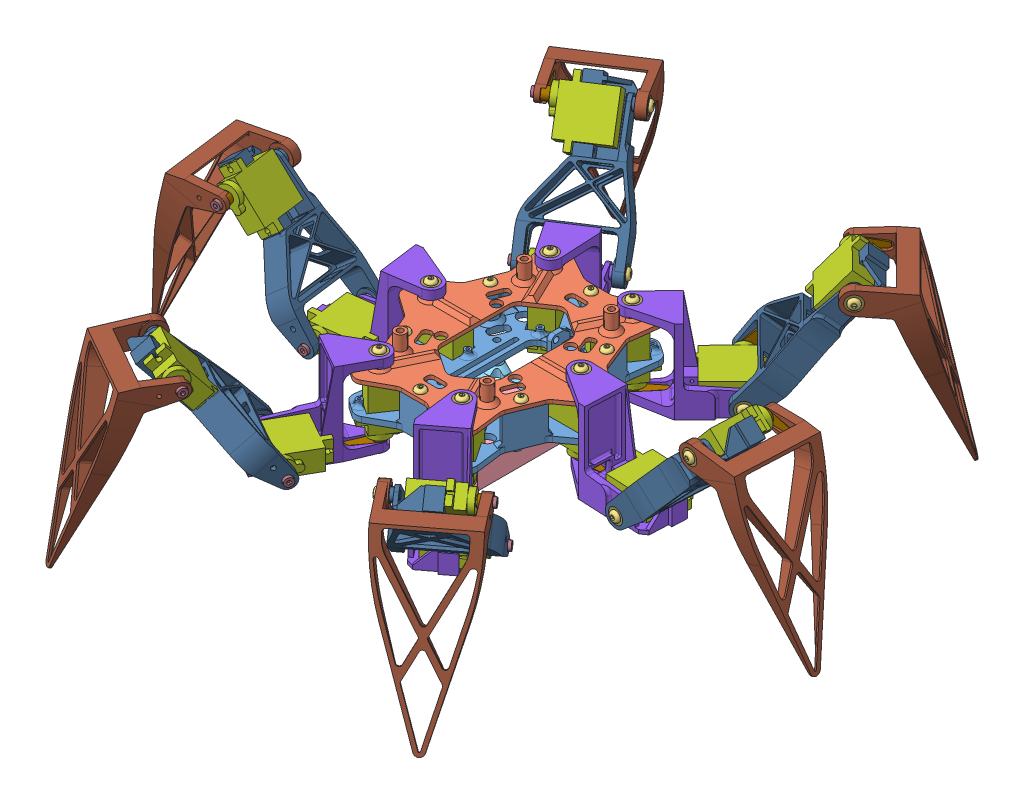
SolidWorks assembly Spider, configuration Default. Lengths in mm.
Overall size (363.71 100.91 356.3).
142 component instances, 13 part files, 63 mates.
Components (placement in the parent):
- Base-1: Base [Default] at (36.3736 62.9905 92.2732) size (103.38 18 115.92)
- Top-1: Top [Default] at (36.3236 80.9905 92.3982) size (103.88 12 115.92)
- m3x8 button-1: m3x8 button [Default] at (67.7613 84.6405 115.5337) x (0 -1 0) z (-0.034129 0 0.999417) size (9.65 5.7 5.7)
- m3x8 button-2: m3x8 button [Default] at (36.3236 84.6405 138.3982) x (0 -1 0) z (0.154828 0 0.987941) size (9.65 5.7 5.7)
- m3x8 button-3: m3x8 button [Default] at (4.8859 84.6405 115.5337) x (0 -1 0) z (0.364161 0 0.931336) size (9.65 5.7 5.7)
- m3x8 button-4: m3x8 button [Default] at (4.8859 84.6405 69.2627) x (0 -1 0) z (0.572348 0 0.820011) size (9.65 5.7 5.7)
- m3x8 button-5: m3x8 button [Default] at (36.3236 84.6405 46.3982) x (0 -1 0) z (0.751604 0 0.659615) size (9.65 5.7 5.7)
- m3x8 button-6: m3x8 button [Default] at (67.7613 84.6405 69.2627) x (0 -1 0) z (0.880548 0 0.473957) size (9.65 5.7 5.7)
- Battery-1: Battery [Default] at (36.3736 35.9905 92.2732) x (0 0 -1) z (1 0 0) size (62 15 31)
- battery_mount-1: battery_mount [Default] at (36.3736 50.9905 92.2732) x (0 0 1) z (-1 0 0) size (36.78 12 46.78)
- threaded insert-4: threaded insert [Default] at (58.6155 81.7905 138.3982) size (4 4.7 4)
- threaded insert-5: threaded insert [Default] at (14.0317 81.7905 138.3982) x (0.982082 0 -0.188455) z (0.188455 0 0.982082) size (4 4.7 4)
- threaded insert-6: threaded insert [Default] at (-4.3683 81.7905 92.3982) x (0.918365 0 -0.395734) z (0.395734 0 0.918365) size (4 4.7 4)
- threaded insert-7: threaded insert [Default] at (14.0317 81.7905 46.3982) x (0.8 0 -0.6) z (0.6 0 0.8) size (4 4.7 4)
- threaded insert-8: threaded insert [Default] at (58.6155 81.7905 46.3982) x (0.63358 0 -0.773678) z (0.773678 0 0.63358) size (4 4.7 4)
- threaded insert-9: threaded insert [Default] at (77.0155 81.7905 92.3982) x (0.443629 0 -0.896211) z (0.896211 0 0.443629) size (4 4.7 4)
- MG90S Servo-1: MG90S Servo [Default] at (55.3718 78.9905 133.4083) x (0.560629 0 0.828067) z (0.828067 0 -0.560629) size (32 30 11)
- MG90S Servo-2: MG90S Servo [Default] at (70.9405 78.9905 92.2732) x (1 0 0) z (0 0 -1) size (32 30 11)
- MG90S Servo-3: MG90S Servo [Default] at (55.3718 78.9905 51.1381) x (0.560629 0 -0.828067) z (-0.828067 0 -0.560629) size (32 30 11)
- MG90S Servo-4: MG90S Servo [Default] at (17.3754 78.9905 51.1381) x (-0.560629 0 -0.828067) z (-0.828067 0 0.560629) size (32 30 11)
- MG90S Servo-5: MG90S Servo [Default] at (1.8067 78.9905 92.2732) x (-1 0 0) z (0 0 1) size (32 30 11)
- MG90S Servo-6: MG90S Servo [Default] at (17.3754 78.9905 133.4083) x (-0.560629 0 0.828067) z (0.828067 0 0.560629) size (32 30 11)
- leg-9: leg [Default] at (95.2085 35.4236 45.2462) x (0.998917 0 0.046534) z (-0.046534 0 0.998917) size (145.56 100.91 49.06)
  - hip-1: hip [Default] at (3.5209 10.0668 41.9475) size (59.25 45 23)
  - MG90S Servo-1: MG90S Servo [Default] at (20.5209 18.3168 57.9475) x (1 0 0) z (0 1 0) size (32 30 11)
  - servo horn-1: servo horn [Default] at (26.5209 18.3168 26.9475) x (0.646712 0.762734 0) z (0.762734 -0.646712 0) size (17.5 3.5 6)
  - threaded insert-1: threaded insert [Default] at (26.5209 18.3168 64.9475) x (-0.923728 -0.383049 0) z (0.383049 -0.923728 0) size (4 4.7 4)
  - thigh-1: thigh [Default] at (59.9753 45.0163 41.9475) x (0.646712 0.762734 0) z (0 0 1) size (81.75 14.22 44.5)
  - MG90S Servo-2: MG90S Servo [Default] at (64.6769 63.3181 57.9475) x (0.646712 0.762734 0) z (-0.762734 0.646712 0) size (32 30 11)
  - threaded insert-2: threaded insert [Default] at (68.5572 67.8945 60.2475) x (-0.923728 -0.383049 0) z (-0.383049 0.923728 0) size (4 4.7 4)
  - servo horn-2: servo horn [Default] at (68.5572 67.8945 26.9475) x (0.996071 -0.088554 0) z (-0.088554 -0.996071 0) size (17.5 3.5 6)
  - shin curved-1: shin curved [Default] at (168.1643 59.0391 46.6975) x (0 0 -1) z (0.088554 0.996071 0) size (49.06 60.96 90.13)
  - 693zz-1: 693zz [Default] at (26.5209 18.3168 64.9475) x (0.87068 -0.491851 0) z (-0.491851 -0.87068 0) size (8 4 8)
  - 693zz-2: 693zz [Default] at (68.5572 67.8945 64.9475) x (0.93765 -0.34758 0) z (-0.34758 -0.93765 0) size (8 4 8)
  - m3x8 button-1: m3x8 button [Default] at (26.5209 18.3168 70.5975) x (0 0 -1) z (1 0 0) size (9.65 5.7 5.7)
  - m3x8 button-5: m3x8 button [Default] at (68.5572 67.8945 70.5975) x (0 0 -1) z (1 0 0) size (9.65 5.7 5.7)
  - M2.5X8 Cap Head-1: M2.5X8 Cap Head [Default] at (26.5209 18.3168 22.9475) x (0 0 1) z (-0.556527 0.83083 0) size (8.5 4.5 4.5)
  - M2.5X8 Cap Head-2: M2.5X8 Cap Head [Default] at (68.5572 67.8945 22.9475) x (0 0 1) z (0.690395 0.723432 0) size (8.5 4.5 4.5)
  - servo horn-3: servo horn [Default] at (-15.9791 12.5668 47.9475) size (17.5 3.5 6)
  - 693zz-4: 693zz [Default] at (-15.9791 51.0668 47.9475) x (0.999788 0 -0.020572) z (0.020572 0 0.999788) size (8 4 8)
  - m3x8 button-7: m3x8 button [Default] at (-15.9791 56.7168 47.9475) x (0 -1 0) z (1 0 0) size (9.65 5.7 5.7)
  - M2.5X8 Cap Head-3: M2.5X8 Cap Head [Default] at (-15.9791 8.5668 47.9475) x (0 1 0) z (0 0 1) size (8.5 4.5 4.5)
- leg-11: leg [Default] at (35.8596 35.4236 1.271) x (0.704741 0 -0.709465) z (0.709465 0 0.704741) size (145.56 100.91 49.06)
  - hip-1: hip [Default] at (3.5209 10.0668 41.9475) size (59.25 45 23)
  - MG90S Servo-1: MG90S Servo [Default] at (20.5209 18.3168 57.9475) x (1 0 0) z (0 1 0) size (32 30 11)
  - servo horn-1: servo horn [Default] at (26.5209 18.3168 26.9475) x (0.646712 0.762734 0) z (0.762734 -0.646712 0) size (17.5 3.5 6)
  - threaded insert-1: threaded insert [Default] at (26.5209 18.3168 64.9475) x (-0.923728 -0.383049 0) z (0.383049 -0.923728 0) size (4 4.7 4)
  - thigh-1: thigh [Default] at (59.9753 45.0163 41.9475) x (0.646712 0.762734 0) z (0 0 1) size (81.75 14.22 44.5)
  - MG90S Servo-2: MG90S Servo [Default] at (64.6769 63.3181 57.9475) x (0.646712 0.762734 0) z (-0.762734 0.646712 0) size (32 30 11)
  - threaded insert-2: threaded insert [Default] at (68.5572 67.8945 60.2475) x (-0.923728 -0.383049 0) z (-0.383049 0.923728 0) size (4 4.7 4)
  - servo horn-2: servo horn [Default] at (68.5572 67.8945 26.9475) x (0.996071 -0.088554 0) z (-0.088554 -0.996071 0) size (17.5 3.5 6)
  - shin curved-1: shin curved [Default] at (168.1643 59.0391 46.6975) x (0 0 -1) z (0.088554 0.996071 0) size (49.06 60.96 90.13)
  - 693zz-1: 693zz [Default] at (26.5209 18.3168 64.9475) x (0.87068 -0.491851 0) z (-0.491851 -0.87068 0) size (8 4 8)
  - 693zz-2: 693zz [Default] at (68.5572 67.8945 64.9475) x (0.93765 -0.34758 0) z (-0.34758 -0.93765 0) size (8 4 8)
  - m3x8 button-1: m3x8 button [Default] at (26.5209 18.3168 70.5975) x (0 0 -1) z (1 0 0) size (9.65 5.7 5.7)
  - m3x8 button-5: m3x8 button [Default] at (68.5572 67.8945 70.5975) x (0 0 -1) z (1 0 0) size (9.65 5.7 5.7)
  - M2.5X8 Cap Head-1: M2.5X8 Cap Head [Default] at (26.5209 18.3168 22.9475) x (0 0 1) z (-0.556527 0.83083 0) size (8.5 4.5 4.5)
  - M2.5X8 Cap Head-2: M2.5X8 Cap Head [Default] at (68.5572 67.8945 22.9475) x (0 0 1) z (0.690395 0.723432 0) size (8.5 4.5 4.5)
  - servo horn-3: servo horn [Default] at (-15.9791 12.5668 47.9475) size (17.5 3.5 6)
  - 693zz-4: 693zz [Default] at (-15.9791 51.0668 47.9475) x (0.999788 0 -0.020572) z (0.020572 0 0.999788) size (8 4 8)
  - m3x8 button-7: m3x8 button [Default] at (-15.9791 56.7168 47.9475) x (0 -1 0) z (1 0 0) size (9.65 5.7 5.7)
  - M2.5X8 Cap Head-3: M2.5X8 Cap Head [Default] at (-15.9791 8.5668 47.9475) x (0 1 0) z (0 0 1) size (8.5 4.5 4.5)
- leg-13: leg [Default] at (-34.8765 35.4236 58.9854) x (-0.546402 0 -0.837523) z (0.837523 0 -0.546402) size (145.56 100.91 49.06)
  - hip-1: hip [Default] at (3.5209 10.0668 41.9475) size (59.25 45 23)
  - MG90S Servo-1: MG90S Servo [Default] at (20.5209 18.3168 57.9475) x (1 0 0) z (0 1 0) size (32 30 11)
  - servo horn-1: servo horn [Default] at (26.5209 18.3168 26.9475) x (0.646712 0.762734 0) z (0.762734 -0.646712 0) size (17.5 3.5 6)
  - threaded insert-1: threaded insert [Default] at (26.5209 18.3168 64.9475) x (-0.923728 -0.383049 0) z (0.383049 -0.923728 0) size (4 4.7 4)
  - thigh-1: thigh [Default] at (59.9753 45.0163 41.9475) x (0.646712 0.762734 0) z (0 0 1) size (81.75 14.22 44.5)
  - MG90S Servo-2: MG90S Servo [Default] at (64.6769 63.3181 57.9475) x (0.646712 0.762734 0) z (-0.762734 0.646712 0) size (32 30 11)
  - threaded insert-2: threaded insert [Default] at (68.5572 67.8945 60.2475) x (-0.923728 -0.383049 0) z (-0.383049 0.923728 0) size (4 4.7 4)
  - servo horn-2: servo horn [Default] at (68.5572 67.8945 26.9475) x (0.996071 -0.088554 0) z (-0.088554 -0.996071 0) size (17.5 3.5 6)
  - shin curved-1: shin curved [Default] at (168.1643 59.0391 46.6975) x (0 0 -1) z (0.088554 0.996071 0) size (49.06 60.96 90.13)
  - 693zz-1: 693zz [Default] at (26.5209 18.3168 64.9475) x (0.87068 -0.491851 0) z (-0.491851 -0.87068 0) size (8 4 8)
  - 693zz-2: 693zz [Default] at (68.5572 67.8945 64.9475) x (0.93765 -0.34758 0) z (-0.34758 -0.93765 0) size (8 4 8)
  - m3x8 button-1: m3x8 button [Default] at (26.5209 18.3168 70.5975) x (0 0 -1) z (1 0 0) size (9.65 5.7 5.7)
  - m3x8 button-5: m3x8 button [Default] at (68.5572 67.8945 70.5975) x (0 0 -1) z (1 0 0) size (9.65 5.7 5.7)
  - M2.5X8 Cap Head-1: M2.5X8 Cap Head [Default] at (26.5209 18.3168 22.9475) x (0 0 1) z (-0.556527 0.83083 0) size (8.5 4.5 4.5)
  - M2.5X8 Cap Head-2: M2.5X8 Cap Head [Default] at (68.5572 67.8945 22.9475) x (0 0 1) z (0.690395 0.723432 0) size (8.5 4.5 4.5)
  - servo horn-3: servo horn [Default] at (-15.9791 12.5668 47.9475) size (17.5 3.5 6)
  - 693zz-4: 693zz [Default] at (-15.9791 51.0668 47.9475) x (0.999788 0 -0.020572) z (0.020572 0 0.999788) size (8 4 8)
  - m3x8 button-7: m3x8 button [Default] at (-15.9791 56.7168 47.9475) x (0 -1 0) z (1 0 0) size (9.65 5.7 5.7)
  - M2.5X8 Cap Head-3: M2.5X8 Cap Head [Default] at (-15.9791 8.5668 47.9475) x (0 1 0) z (0 0 1) size (8.5 4.5 4.5)
- leg-15: leg [Default] at (-13.8109 35.4236 141.8897) x (-0.991533 0 0.129855) z (-0.129855 0 -0.991533) size (145.56 100.91 49.06)
  - hip-1: hip [Default] at (3.5209 10.0668 41.9475) size (59.25 45 23)
  - MG90S Servo-1: MG90S Servo [Default] at (20.5209 18.3168 57.9475) x (1 0 0) z (0 1 0) size (32 30 11)
  - servo horn-1: servo horn [Default] at (26.5209 18.3168 26.9475) x (0.646712 0.762734 0) z (0.762734 -0.646712 0) size (17.5 3.5 6)
  - threaded insert-1: threaded insert [Default] at (26.5209 18.3168 64.9475) x (-0.923728 -0.383049 0) z (0.383049 -0.923728 0) size (4 4.7 4)
  - thigh-1: thigh [Default] at (59.9753 45.0163 41.9475) x (0.646712 0.762734 0) z (0 0 1) size (81.75 14.22 44.5)
  - MG90S Servo-2: MG90S Servo [Default] at (64.6769 63.3181 57.9475) x (0.646712 0.762734 0) z (-0.762734 0.646712 0) size (32 30 11)
  - threaded insert-2: threaded insert [Default] at (68.5572 67.8945 60.2475) x (-0.923728 -0.383049 0) z (-0.383049 0.923728 0) size (4 4.7 4)
  - servo horn-2: servo horn [Default] at (68.5572 67.8945 26.9475) x (0.996071 -0.088554 0) z (-0.088554 -0.996071 0) size (17.5 3.5 6)
  - shin curved-1: shin curved [Default] at (168.1643 59.0391 46.6975) x (0 0 -1) z (0.088554 0.996071 0) size (49.06 60.96 90.13)
  - 693zz-1: 693zz [Default] at (26.5209 18.3168 64.9475) x (0.87068 -0.491851 0) z (-0.491851 -0.87068 0) size (8 4 8)
  - 693zz-2: 693zz [Default] at (68.5572 67.8945 64.9475) x (0.93765 -0.34758 0) z (-0.34758 -0.93765 0) size (8 4 8)
  - m3x8 button-1: m3x8 button [Default] at (26.5209 18.3168 70.5975) x (0 0 -1) z (1 0 0) size (9.65 5.7 5.7)
  - m3x8 button-5: m3x8 button [Default] at (68.5572 67.8945 70.5975) x (0 0 -1) z (1 0 0) size (9.65 5.7 5.7)
  - M2.5X8 Cap Head-1: M2.5X8 Cap Head [Default] at (26.5209 18.3168 22.9475) x (0 0 1) z (-0.556527 0.83083 0) size (8.5 4.5 4.5)
  - M2.5X8 Cap Head-2: M2.5X8 Cap Head [Default] at (68.5572 67.8945 22.9475) x (0 0 1) z (0.690395 0.723432 0) size (8.5 4.5 4.5)
  - servo horn-3: servo horn [Default] at (-15.9791 12.5668 47.9475) size (17.5 3.5 6)
  - 693zz-4: 693zz [Default] at (-15.9791 51.0668 47.9475) x (0.999788 0 -0.020572) z (0.020572 0 0.999788) size (8 4 8)
  - m3x8 button-7: m3x8 button [Default] at (-15.9791 56.7168 47.9475) x (0 -1 0) z (1 0 0) size (9.65 5.7 5.7)
  - M2.5X8 Cap Head-3: M2.5X8 Cap Head [Default] at (-15.9791 8.5668 47.9475) x (0 1 0) z (0 0 1) size (8.5 4.5 4.5)
- leg-17: leg [Default] at (47.7955 35.4236 175.9659) x (-0.494254 0 0.869317) z (-0.869317 0 -0.494254) size (145.56 100.91 49.06)
  - hip-1: hip [Default] at (3.5209 10.0668 41.9475) size (59.25 45 23)
  - MG90S Servo-1: MG90S Servo [Default] at (20.5209 18.3168 57.9475) x (1 0 0) z (0 1 0) size (32 30 11)
  - servo horn-1: servo horn [Default] at (26.5209 18.3168 26.9475) x (0.646712 0.762734 0) z (0.762734 -0.646712 0) size (17.5 3.5 6)
  - threaded insert-1: threaded insert [Default] at (26.5209 18.3168 64.9475) x (-0.923728 -0.383049 0) z (0.383049 -0.923728 0) size (4 4.7 4)
  - thigh-1: thigh [Default] at (59.9753 45.0163 41.9475) x (0.646712 0.762734 0) z (0 0 1) size (81.75 14.22 44.5)
  - MG90S Servo-2: MG90S Servo [Default] at (64.6769 63.3181 57.9475) x (0.646712 0.762734 0) z (-0.762734 0.646712 0) size (32 30 11)
  - threaded insert-2: threaded insert [Default] at (68.5572 67.8945 60.2475) x (-0.923728 -0.383049 0) z (-0.383049 0.923728 0) size (4 4.7 4)
  - servo horn-2: servo horn [Default] at (68.5572 67.8945 26.9475) x (0.996071 -0.088554 0) z (-0.088554 -0.996071 0) size (17.5 3.5 6)
  - shin curved-1: shin curved [Default] at (168.1643 59.0391 46.6975) x (0 0 -1) z (0.088554 0.996071 0) size (49.06 60.96 90.13)
  - 693zz-1: 693zz [Default] at (26.5209 18.3168 64.9475) x (0.87068 -0.491851 0) z (-0.491851 -0.87068 0) size (8 4 8)
  - 693zz-2: 693zz [Default] at (68.5572 67.8945 64.9475) x (0.93765 -0.34758 0) z (-0.34758 -0.93765 0) size (8 4 8)
  - m3x8 button-1: m3x8 button [Default] at (26.5209 18.3168 70.5975) x (0 0 -1) z (1 0 0) size (9.65 5.7 5.7)
  - m3x8 button-5: m3x8 button [Default] at (68.5572 67.8945 70.5975) x (0 0 -1) z (1 0 0) size (9.65 5.7 5.7)
  - M2.5X8 Cap Head-1: M2.5X8 Cap Head [Default] at (26.5209 18.3168 22.9475) x (0 0 1) z (-0.556527 0.83083 0) size (8.5 4.5 4.5)
  - M2.5X8 Cap Head-2: M2.5X8 Cap Head [Default] at (68.5572 67.8945 22.9475) x (0 0 1) z (0.690395 0.723432 0) size (8.5 4.5 4.5)
  - servo horn-3: servo horn [Default] at (-15.9791 12.5668 47.9475) size (17.5 3.5 6)
  - 693zz-4: 693zz [Default] at (-15.9791 51.0668 47.9475) x (0.999788 0 -0.020572) z (0.020572 0 0.999788) size (8 4 8)
  - m3x8 button-7: m3x8 button [Default] at (-15.9791 56.7168 47.9475) x (0 -1 0) z (1 0 0) size (9.65 5.7 5.7)
  - M2.5X8 Cap Head-3: M2.5X8 Cap Head [Default] at (-15.9791 8.5668 47.9475) x (0 1 0) z (0 0 1) size (8.5 4.5 4.5)
- leg-19: leg [Default] at (106.5656 35.4236 122.0493) x (0.605702 0 0.795692) z (-0.795692 0 0.605702) size (145.56 100.91 49.06)
  - hip-1: hip [Default] at (3.5209 10.0668 41.9475) size (59.25 45 23)
  - MG90S Servo-1: MG90S Servo [Default] at (20.5209 18.3168 57.9475) x (1 0 0) z (0 1 0) size (32 30 11)
  - servo horn-1: servo horn [Default] at (26.5209 18.3168 26.9475) x (0.646712 0.762734 0) z (0.762734 -0.646712 0) size (17.5 3.5 6)
  - threaded insert-1: threaded insert [Default] at (26.5209 18.3168 64.9475) x (-0.923728 -0.383049 0) z (0.383049 -0.923728 0) size (4 4.7 4)
  - thigh-1: thigh [Default] at (59.9753 45.0163 41.9475) x (0.646712 0.762734 0) z (0 0 1) size (81.75 14.22 44.5)
  - MG90S Servo-2: MG90S Servo [Default] at (64.6769 63.3181 57.9475) x (0.646712 0.762734 0) z (-0.762734 0.646712 0) size (32 30 11)
  - threaded insert-2: threaded insert [Default] at (68.5572 67.8945 60.2475) x (-0.923728 -0.383049 0) z (-0.383049 0.923728 0) size (4 4.7 4)
  - servo horn-2: servo horn [Default] at (68.5572 67.8945 26.9475) x (0.996071 -0.088554 0) z (-0.088554 -0.996071 0) size (17.5 3.5 6)
  - shin curved-1: shin curved [Default] at (168.1643 59.0391 46.6975) x (0 0 -1) z (0.088554 0.996071 0) size (49.06 60.96 90.13)
  - 693zz-1: 693zz [Default] at (26.5209 18.3168 64.9475) x (0.87068 -0.491851 0) z (-0.491851 -0.87068 0) size (8 4 8)
  - 693zz-2: 693zz [Default] at (68.5572 67.8945 64.9475) x (0.93765 -0.34758 0) z (-0.34758 -0.93765 0) size (8 4 8)
  - m3x8 button-1: m3x8 button [Default] at (26.5209 18.3168 70.5975) x (0 0 -1) z (1 0 0) size (9.65 5.7 5.7)
  - m3x8 button-5: m3x8 button [Default] at (68.5572 67.8945 70.5975) x (0 0 -1) z (1 0 0) size (9.65 5.7 5.7)
  - M2.5X8 Cap Head-1: M2.5X8 Cap Head [Default] at (26.5209 18.3168 22.9475) x (0 0 1) z (-0.556527 0.83083 0) size (8.5 4.5 4.5)
  - M2.5X8 Cap Head-2: M2.5X8 Cap Head [Default] at (68.5572 67.8945 22.9475) x (0 0 1) z (0.690395 0.723432 0) size (8.5 4.5 4.5)
  - servo horn-3: servo horn [Default] at (-15.9791 12.5668 47.9475) size (17.5 3.5 6)
  - 693zz-4: 693zz [Default] at (-15.9791 51.0668 47.9475) x (0.999788 0 -0.020572) z (0.020572 0 0.999788) size (8 4 8)
  - m3x8 button-7: m3x8 button [Default] at (-15.9791 56.7168 47.9475) x (0 -1 0) z (1 0 0) size (9.65 5.7 5.7)
  - M2.5X8 Cap Head-3: M2.5X8 Cap Head [Default] at (-15.9791 8.5668 47.9475) x (0 1 0) z (0 0 1) size (8.5 4.5 4.5)
Mates (geometry in assembly coordinates):
- Concentric2: concentric anti-aligned: cylinder of Base-1 through (67.7613 80.9905 115.5337) axis (0 -1 0) radius 2; cylinder of Top-1 through (67.7613 72.9905 115.5337) axis (0 1 0) radius 1.6
- Parallel2: parallel anti-aligned: cylinder of Base-1 through (36.3736 80.9905 46.2732) axis (0 -1 0) radius 2; cylinder of Top-1 through (36.3236 72.9905 46.3982) axis (0 1 0) radius 1.6
- Coincident3: coincident anti-aligned: plane of Base-1 through (36.3736 80.9905 92.2732) normal (0 1 0); plane of Top-1 through (36.3236 80.9905 92.3982) normal (0 -1 0)
- Coincident4: coincident anti-aligned: plane of Top-1 through (36.3236 82.9905 92.3982) normal (0 1 0); plane of m3x8 button-1 through (67.8125 82.9905 114.0346) normal (0 -1 0)
- Concentric4: concentric anti-aligned: cylinder of Top-1 through (67.7613 72.9905 115.5337) axis (0 1 0) radius 1.6; cylinder of m3x8 button-1 through (67.7613 84.6405 115.5337) axis (0 -1 0) radius 2.85
- Coincident5: coincident anti-aligned: plane of Top-1 through (36.3236 82.9905 92.3982) normal (0 1 0); plane of m3x8 button-2 through (36.0914 82.9905 136.9163) normal (0 -1 0)
- Concentric5: concentric anti-aligned: cylinder of Top-1 through (36.3236 72.9905 138.3982) axis (0 1 0) radius 1.6; cylinder of m3x8 button-2 through (36.3236 84.6405 138.3982) axis (0 -1 0) radius 2.85
- Coincident6: coincident anti-aligned: plane of Top-1 through (36.3236 82.9905 92.3982) normal (0 1 0); plane of m3x8 button-3 through (4.3397 82.9905 114.1367) normal (0 -1 0)
- Concentric6: concentric anti-aligned: cylinder of Top-1 through (4.8859 72.9905 115.5337) axis (0 1 0) radius 1.6; cylinder of m3x8 button-3 through (4.8859 84.6405 115.5337) axis (0 -1 0) radius 2.85
- Coincident7: coincident anti-aligned: plane of Top-1 through (36.3236 82.9905 92.3982) normal (0 1 0); plane of m3x8 button-4 through (4.0274 82.9905 68.0327) normal (0 -1 0)
- Concentric7: concentric anti-aligned: cylinder of Top-1 through (4.8859 72.9905 69.2627) axis (0 1 0) radius 1.6; cylinder of m3x8 button-4 through (4.8859 84.6405 69.2627) axis (0 -1 0) radius 2.85
- Coincident8: coincident anti-aligned: plane of Top-1 through (36.3236 82.9905 92.3982) normal (0 1 0); plane of m3x8 button-5 through (35.1962 82.9905 45.4088) normal (0 -1 0)
- Concentric8: concentric anti-aligned: cylinder of Top-1 through (36.3236 72.9905 46.3982) axis (0 1 0) radius 1.6; cylinder of m3x8 button-5 through (36.3236 84.6405 46.3982) axis (0 -1 0) radius 2.85
- Coincident9: coincident anti-aligned: plane of Top-1 through (36.3236 82.9905 92.3982) normal (0 1 0); plane of m3x8 button-6 through (66.4404 82.9905 68.5518) normal (0 -1 0)
- Concentric9: concentric anti-aligned: cylinder of Top-1 through (67.7613 72.9905 69.2627) axis (0 1 0) radius 1.6; cylinder of m3x8 button-6 through (67.7613 84.6405 69.2627) axis (0 -1 0) radius 2.85
- Concentric17: concentric aligned: cylinder of Base-1 through (4.8859 80.9905 69.2627) axis (0 -1 0) radius 4; cylinder of m3x8 button-4 through (4.8859 84.6405 69.2627) axis (0 -1 0) radius 1.5
- Width2: width anti-aligned: plane of Battery-1 through (51.8736 50.9905 123.2732) normal (0 0 1); plane of Battery-1 through (51.8736 50.9905 61.2732) normal (0 0 -1); plane of Base-1 through (11.3736 65.9905 42.2732) normal (0 0 -1); plane of Base-1 through (61.3736 65.9905 142.2732) normal (0 0 1)
- Concentric19: concentric anti-aligned: cylinder of Base-1 through (16.3736 53.4905 77.2732) axis (0 1 0) radius 1.6; cylinder of battery_mount-1 through (16.3736 52.9905 77.2732) axis (0 -1 0) radius 3
- Concentric20: concentric anti-aligned: cylinder of Base-1 through (16.3736 53.4905 107.2732) axis (0 1 0) radius 1.6; cylinder of battery_mount-1 through (16.3736 52.9905 107.2732) axis (0 -1 0) radius 3
- Coincident18: coincident anti-aligned: plane of Base-1 through (36.3736 62.9905 92.2732) normal (0 -1 0); plane of battery_mount-1 through (16.3736 62.9905 77.2732) normal (0 1 0)
- Coincident19: coincident anti-aligned: plane of Battery-1 through (36.3736 50.9905 92.2732) normal (0 1 0); plane of battery_mount-1 through (56.3736 50.9905 77.2732) normal (0 -1 0)
- Concentric21: concentric aligned: cylinder of Top-1 through (58.6155 86.4905 138.3982) axis (0 -1 0) radius 2; cylinder of threaded insert-4 through (58.6155 86.4905 138.3982) axis (0 -1 0) radius 2
- Coincident21: coincident aligned: plane of Top-1 through (58.6155 86.4905 138.3982) normal (0 1 0); plane of threaded insert-4 through (58.6155 86.4905 138.3982) normal (0 1 0)
- Concentric22: concentric aligned: cylinder of Top-1 through (14.0317 86.4905 138.3982) axis (0 -1 0) radius 2; cylinder of threaded insert-5 through (14.0317 86.4905 138.3982) axis (0 -1 0) radius 2
- Coincident22: coincident aligned: plane of Top-1 through (58.6155 86.4905 138.3982) normal (0 1 0); plane of threaded insert-5 through (14.0317 86.4905 138.3982) normal (0 1 0)
- Coincident23: coincident aligned: plane of Top-1 through (58.6155 86.4905 138.3982) normal (0 1 0); plane of threaded insert-6 through (-4.3683 86.4905 92.3982) normal (0 1 0)
- Concentric23: concentric aligned: cylinder of Top-1 through (-4.3683 86.4905 92.3982) axis (0 -1 0) radius 2; cylinder of threaded insert-6 through (-4.3683 86.4905 92.3982) axis (0 -1 0) radius 2
- Coincident24: coincident aligned: plane of Top-1 through (58.6155 86.4905 138.3982) normal (0 1 0); plane of threaded insert-7 through (14.0317 86.4905 46.3982) normal (0 1 0)
- Concentric24: concentric aligned: cylinder of Top-1 through (14.0317 86.4905 46.3982) axis (0 -1 0) radius 2; cylinder of threaded insert-7 through (14.0317 86.4905 46.3982) axis (0 -1 0) radius 2
- Coincident25: coincident aligned: plane of Top-1 through (58.6155 86.4905 138.3982) normal (0 1 0); plane of threaded insert-8 through (58.6155 86.4905 46.3982) normal (0 1 0)
- Concentric25: concentric aligned: cylinder of Top-1 through (58.6155 86.4905 46.3982) axis (0 -1 0) radius 2; cylinder of threaded insert-8 through (58.6155 86.4905 46.3982) axis (0 -1 0) radius 2
- Coincident26: coincident aligned: plane of Top-1 through (58.6155 86.4905 138.3982) normal (0 1 0); plane of threaded insert-9 through (77.0155 86.4905 92.3982) normal (0 1 0)
- Concentric26: concentric aligned: cylinder of Top-1 through (77.0155 86.4905 92.3982) axis (0 -1 0) radius 2; cylinder of threaded insert-9 through (77.0155 86.4905 92.3982) axis (0 -1 0) radius 2
- Concentric27: concentric aligned: cylinder of Top-1 through (77.0155 86.4905 92.3982) axis (0 -1 0) radius 3; cylinder of leg-9/m3x8 button-7 through (77.0155 92.1405 92.3982) axis (0 -1 0) radius 1.5
- Concentric28: concentric anti-aligned: cylinder of Base-1 through (63.0804 55.9905 144.7942) axis (0 1 0) radius 0.75; cylinder of MG90S Servo-1 through (63.0804 63.9905 144.7942) axis (0 -1 0) radius 1.25
- Concentric30: concentric anti-aligned: cylinder of Base-1 through (47.6631 55.9905 122.0224) axis (0 1 0) radius 0.75; cylinder of MG90S Servo-1 through (47.6631 63.9905 122.0224) axis (0 -1 0) radius 1.25
- Coincident29: coincident anti-aligned: plane of Base-1 through (36.3736 62.9905 92.2732) normal (0 -1 0); plane of MG90S Servo-1 through (50.9561 62.9905 117.0758) normal (0 1 0)
- Concentric31: concentric anti-aligned: cylinder of Base-1 through (84.6905 55.9905 92.2732) axis (0 1 0) radius 0.75; cylinder of MG90S Servo-2 through (84.6905 63.9905 92.2732) axis (0 -1 0) radius 1.25
- Concentric32: concentric anti-aligned: cylinder of Base-1 through (57.1905 55.9905 92.2732) axis (0 1 0) radius 0.75; cylinder of MG90S Servo-2 through (57.1905 63.9905 92.2732) axis (0 -1 0) radius 1.25
- Coincident30: coincident anti-aligned: plane of Base-1 through (36.3736 62.9905 92.2732) normal (0 -1 0); plane of MG90S Servo-2 through (54.9405 62.9905 86.7732) normal (0 1 0)
- Coincident31: coincident anti-aligned: plane of Base-1 through (36.3736 62.9905 92.2732) normal (0 -1 0); plane of MG90S Servo-3 through (41.8473 62.9905 61.3037) normal (0 1 0)
- Concentric33: concentric anti-aligned: cylinder of Base-1 through (63.0804 55.9905 39.7522) axis (0 1 0) radius 0.75; cylinder of MG90S Servo-3 through (63.0804 63.9905 39.7522) axis (0 -1 0) radius 1.25
- Concentric34: concentric anti-aligned: cylinder of Base-1 through (47.6631 55.9905 62.524) axis (0 1 0) radius 0.75; cylinder of MG90S Servo-3 through (47.6631 63.9905 62.524) axis (0 -1 0) radius 1.25
- Coincident32: coincident anti-aligned: plane of Base-1 through (36.3736 62.9905 92.2732) normal (0 -1 0); plane of MG90S Servo-4 through (21.7911 62.9905 67.4706) normal (0 1 0)
- Concentric35: concentric anti-aligned: cylinder of Base-1 through (9.6668 55.9905 39.7522) axis (0 1 0) radius 0.75; cylinder of MG90S Servo-4 through (9.6668 63.9905 39.7522) axis (0 -1 0) radius 1.25
- Concentric36: concentric anti-aligned: cylinder of Base-1 through (25.0841 55.9905 62.524) axis (0 1 0) radius 0.75; cylinder of MG90S Servo-4 through (25.0841 63.9905 62.524) axis (0 -1 0) radius 1.25
- Coincident33: coincident anti-aligned: plane of Base-1 through (36.3736 62.9905 92.2732) normal (0 -1 0); plane of MG90S Servo-5 through (17.8067 62.9905 97.7732) normal (0 1 0)
- Concentric37: concentric anti-aligned: cylinder of Base-1 through (-11.9433 55.9905 92.2732) axis (0 1 0) radius 0.75; cylinder of MG90S Servo-5 through (-11.9433 63.9905 92.2732) axis (0 -1 0) radius 1.25
- Concentric38: concentric anti-aligned: cylinder of Base-1 through (15.5567 55.9905 92.2732) axis (0 1 0) radius 0.75; cylinder of MG90S Servo-5 through (15.5567 63.9905 92.2732) axis (0 -1 0) radius 1.25
- Coincident34: coincident anti-aligned: plane of Base-1 through (36.3736 62.9905 92.2732) normal (0 -1 0); plane of MG90S Servo-6 through (30.8999 62.9905 123.2427) normal (0 1 0)
- Concentric39: concentric anti-aligned: cylinder of Base-1 through (9.6668 55.9905 144.7942) axis (0 1 0) radius 0.75; cylinder of MG90S Servo-6 through (9.6668 63.9905 144.7942) axis (0 -1 0) radius 1.25
- Concentric40: concentric anti-aligned: cylinder of Base-1 through (25.0841 55.9905 122.0224) axis (0 1 0) radius 0.75; cylinder of MG90S Servo-6 through (25.0841 63.9905 122.0224) axis (0 -1 0) radius 1.25
- Coincident36: coincident anti-aligned: plane of MG90S Servo-2 through (76.9405 48.9905 92.2732) normal (0 -1 0); plane of leg-9/servo horn-3 through (77.0155 48.9905 92.3982) normal (0 1 0)
- Coincident39: coincident anti-aligned: plane of MG90S Servo-3 through (58.7356 48.9905 46.1697) normal (0 -1 0); plane of leg-11/servo horn-3 through (58.6155 48.9905 46.3982) normal (0 1 0)
- Concentric43: concentric aligned: cylinder of Top-1 through (58.6155 86.4905 46.3982) axis (0 -1 0) radius 3; cylinder of leg-11/m3x8 button-7 through (58.6155 92.1405 46.3982) axis (0 -1 0) radius 1.5
- Concentric44: concentric aligned: cylinder of MG90S Servo-4 through (14.0117 62.0615 46.1697) axis (0 -1 0) radius 2.5; cylinder of leg-13/m3x8 button-7 through (14.0117 92.1405 46.1697) axis (0 -1 0) radius 1.5
- Coincident40: coincident anti-aligned: plane of MG90S Servo-4 through (14.0117 48.9905 46.1697) normal (0 -1 0); plane of leg-13/servo horn-3 through (14.0117 48.9905 46.1697) normal (0 1 0)
- Concentric45: concentric aligned: cylinder of MG90S Servo-5 through (-4.1933 62.0615 92.2732) axis (0 -1 0) radius 2.5; cylinder of leg-15/m3x8 button-7 through (-4.1933 92.1405 92.2732) axis (0 -1 0) radius 1.5
- Coincident41: coincident anti-aligned: plane of MG90S Servo-5 through (-4.1933 48.9905 92.2732) normal (0 -1 0); plane of leg-15/servo horn-3 through (-4.1933 48.9905 92.2732) normal (0 1 0)
- Concentric46: concentric aligned: cylinder of MG90S Servo-6 through (14.0117 62.0615 138.3767) axis (0 -1 0) radius 2.5; cylinder of leg-17/m3x8 button-7 through (14.0117 92.1405 138.3767) axis (0 -1 0) radius 1.5
- Coincident42: coincident anti-aligned: plane of MG90S Servo-6 through (14.0117 48.9905 138.3767) normal (0 -1 0); plane of leg-17/servo horn-3 through (14.0117 48.9905 138.3767) normal (0 1 0)
- Concentric47: concentric aligned: cylinder of MG90S Servo-1 through (58.7356 62.0615 138.3767) axis (0 -1 0) radius 2.5; cylinder of leg-19/m3x8 button-7 through (58.7356 92.1405 138.3767) axis (0 -1 0) radius 1.5
- Coincident43: coincident anti-aligned: plane of MG90S Servo-1 through (58.7356 48.9905 138.3767) normal (0 -1 0); plane of leg-19/servo horn-3 through (58.7356 48.9905 138.3767) normal (0 1 0)
